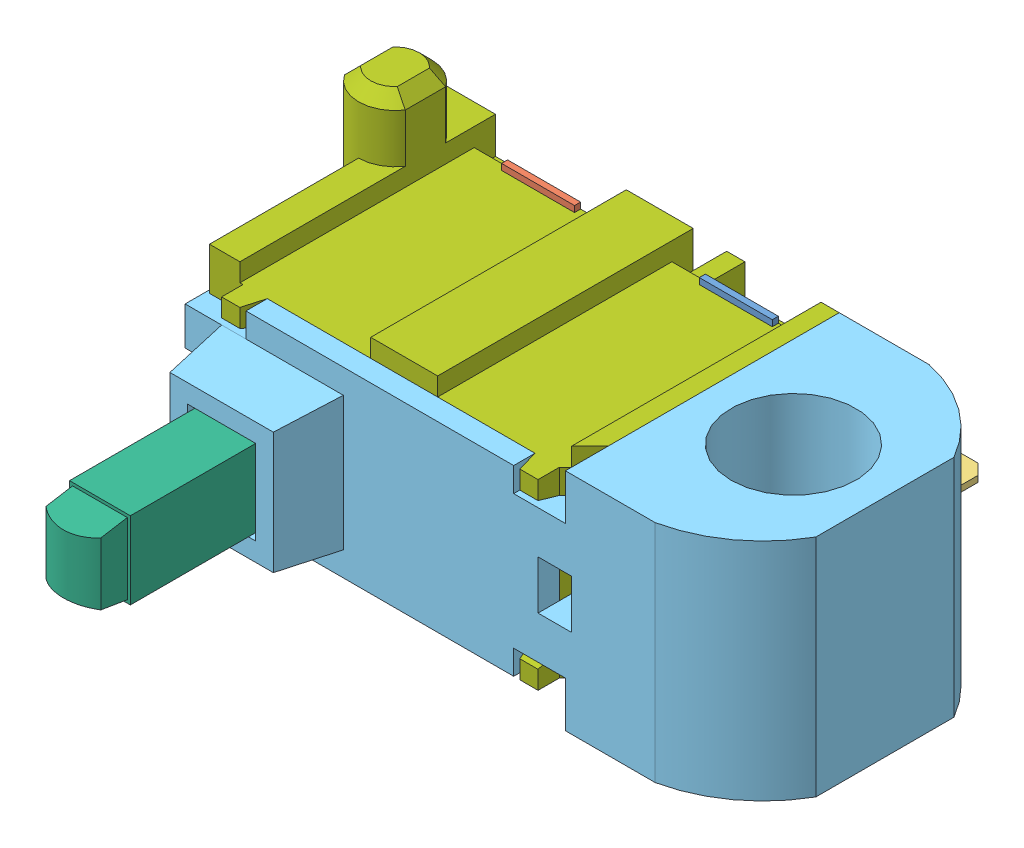
SolidWorks assembly ESE11HS2, configuration Default. Lengths in mm.
Overall size (9.7 5.6 10.55).
7 component instances, 7 part files, 0 mates.
Components (placement in the parent):
- sw-3d-131-e11ts8-hs-sk-r00-1: sw-3d-131-e11ts8-hs-sk-r00 [Default] at (0.1528 0.1 -0.1024) x (1 0 0) z (0 1 0) size (1.2 0.1 0.1)
- sw-3d-131-e11ts8-hs-sk-r00_2-1: sw-3d-131-e11ts8-hs-sk-r00_2 [Default] at (0.1528 0.1 -0.1024) x (1 0 0) z (0 1 0) size (1.2 0.1 0.1)
- sw-3d-131-e11ts8-hs-sk-r00_3-1: sw-3d-131-e11ts8-hs-sk-r00_3 [Default] at (0.1528 0.1 -0.1024) x (1 0 0) z (0 1 0) size (1.91 2.85 0.2)
- sw-3d-131-e11ts8-hs-sk-r00_4-1: sw-3d-131-e11ts8-hs-sk-r00_4 [Default] at (0.1528 0.1 -0.1024) x (1 0 0) z (0 1 0) size (1.6 2.85 0.2)
- sw-3d-131-e11cv9a-hs-sk-r00-1: sw-3d-131-e11cv9a-hs-sk-r00 [Default] at (12.1369 -8.7773 2.4476) size (9.25 3.7 5.5)
- sw-3d-131-e11lv9-hs-sk-r00-1: sw-3d-131-e11lv9-hs-sk-r00 [Default] at (-1.5722 1.8 2.0976) size (1 1.27 3.95)
- sw-3d-131-e11cs3-hs-pc-r00-1: sw-3d-131-e11cs3-hs-pc-r00 [Default] at origin size (6.65 5.6 5.7)
